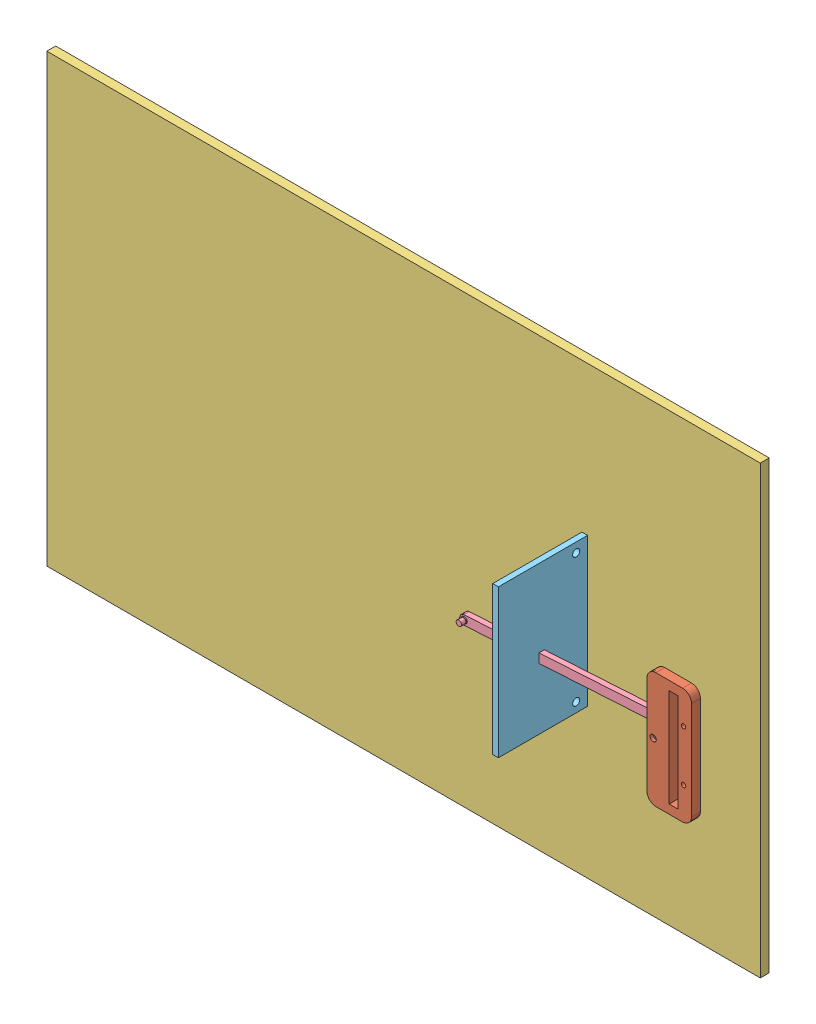
SolidWorks assembly Earthquake Monster, configuration Default. Lengths in mm.
Overall size (800 500 110).
5 component instances, 5 part files, 10 mates.
Components (placement in the parent):
- Hitch Interface-1: Hitch Interface [Default] at (278.9494 70.0195 153.4728) x (1 0 0) z (0 1 0) size (24 18 24)
- TrailerHitch-1: TrailerHitch [Default] at (271.9494 135.0195 147.1228) x (0 -1 0) z (0 0 1) size (130 50 10)
- Floor-1: Floor [Default] at (-78.0506 70.0195 70.0228) size (800 500 10)
- Connecting Rod-1: Connecting Rod [Default] at (222.7995 66.6649 128.4728) x (0.99822 0.059637 0) z (0 0 1) size (245 10.2 12)
- End Rail-1: End Rail [Default] at (128.2994 70.0195 130.0228) x (0 -1 0) z (-1 0 0) size (166 100 6.35)
Mates (geometry in assembly coordinates):
- Distance1: distance = 77.1 mm aligned: plane of Floor-1 through (-78.0506 70.0195 80.0228) normal (0 0 1); plane of TrailerHitch-1 through (271.9494 135.0195 157.1228) normal (0 0 1)
- Coincident2: coincident aligned: plane of TrailerHitch-1 through (321.9494 135.0195 157.1228) normal (1 0 0); plane of Floor-1 through (321.9494 320.0195 80.0228) normal (1 0 0)
- Width1: width aligned: plane of Floor-1 through (-478.0506 -179.9805 80.0228) normal (0 -1 0); plane of Floor-1 through (-478.0506 320.0195 80.0228) normal (0 1 0); plane of TrailerHitch-1 through (271.9494 5.0195 157.1228) normal (0 -1 0); plane of TrailerHitch-1 through (271.9494 135.0195 157.1228) normal (0 1 0)
- Concentric1: concentric aligned: cylinder of Hitch Interface-1 through (278.9494 70.0195 143.4728) axis (0 0 -1) radius 3.6; cylinder of TrailerHitch-1 through (278.9494 70.0195 157.1228) axis (0 0 -1) radius 3.5
- Coincident3: coincident anti-aligned: plane of Hitch Interface-1 through (282.5494 70.0195 147.1228) normal (0 0 1); plane of TrailerHitch-1 through (271.9494 135.0195 147.1228) normal (0 0 -1)
- Concentric2: concentric aligned: cylinder of Hitch Interface-1 through (278.9494 70.0195 143.4728) axis (0 0 -1) radius 6.56; cylinder of Connecting Rod-1 through (278.9494 70.0195 140.4728) axis (0 0 -1) radius 3
- Coincident4: coincident anti-aligned: plane of Hitch Interface-1 through (290.9494 70.0195 135.4728) normal (0 0 -1); plane of Connecting Rod-1 through (278.9494 70.0195 135.4728) normal (0 0 1)
- Coincident5: coincident anti-aligned: plane of Floor-1 through (-78.0506 70.0195 80.0228) normal (0 0 1); plane of End Rail-1 through (121.9494 153.0195 80.0228) normal (0 0 -1)
- Distance2: distance = 200 mm anti-aligned: plane of End Rail-1 through (121.9494 70.0195 130.0228) normal (-1 0 0); plane of Floor-1 through (321.9494 320.0195 80.0228) normal (1 0 0)
- Distance3: distance = 18 mm aligned: plane of End Rail-1 through (121.9494 153.0195 180.0228) normal (0 1 0); plane of TrailerHitch-1 through (271.9494 135.0195 157.1228) normal (0 1 0)
